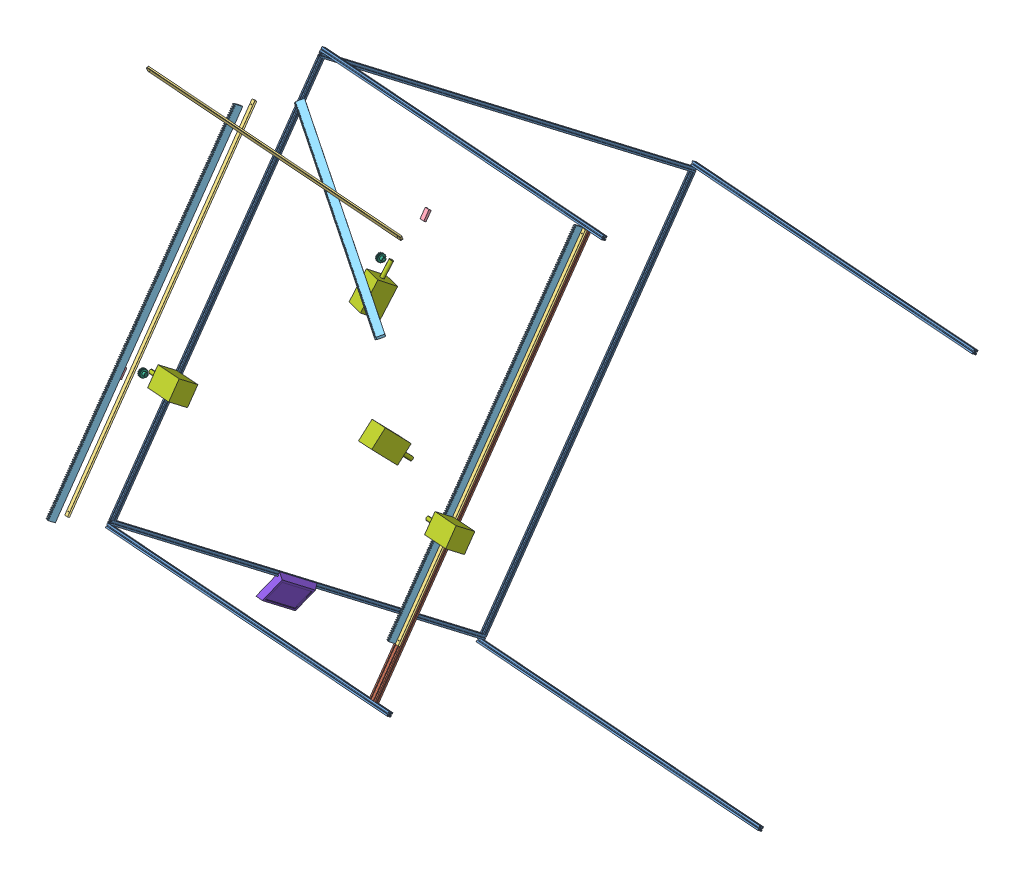
SolidWorks assembly Paketleme Kartezyen Robotu_Exoskeleton, configuration Varsayılan. Lengths in mm.
Overall size (2459.18 3444.17 3173.2).
27 component instances, 8 part files, 54 mates.
Components (placement in the parent):
- Sigma Profil-1: Sigma Profil [Varsayılan<Makinelenmiş Olarak>] at (-2463.5202 2459.5704 -5091.3721) x (0.236079 -0.555945 -0.796989) z (0.97173 0.132881 0.195148) size (20 20 2000)
- Sigma Profil-2: Sigma Profil [Varsayılan<Makinelenmiş Olarak>] at (-992.8245 2135.815 -1945.5437) x (-0.002587 -0.820529 0.571599) z (-0.97173 -0.132881 -0.195148) size (20 20 2000)
- Sigma Profil-3: Sigma Profil [Varsayılan<Makinelenmiş Olarak>] at (-2456.7194 781.4613 -3931.3276) x (0.97173 0.132881 0.195148) z (-0.236079 0.555945 0.796989) size (20 20 2000)
- Sigma Profil-4: Sigma Profil [Varsayılan<Makinelenmiş Olarak>] at (-2923.6516 3550.8201 -3491.9806) x (0.97173 0.132881 0.195148) z (0.236079 -0.555945 -0.796989) size (20 20 2000)
- Sigma Profil-5: Sigma Profil [Varsayılan<Makinelenmiş Olarak>] at (-2930.9564 3560.3424 -3513.3339) x (0.236079 -0.555945 -0.796989) z (0.97173 0.132881 0.195148) size (20 20 2000)
- Sigma Profil-6: Sigma Profil [Varsayılan<Makinelenmiş Olarak>] at (-525.3883 1035.043 -3523.5818) x (-0.002587 -0.820529 0.571599) z (-0.97173 -0.132881 -0.195148) size (20 20 2000)
- Sigma Profil-7: Sigma Profil [Varsayılan<Makinelenmiş Olarak>] at (-2453.8805 2436.2834 -5072.2726) x (0.97173 0.132881 0.195148) z (-0.002587 -0.820529 0.571599) size (20 20 2000)
- Sigma Profil-8: Sigma Profil [Varsayılan<Makinelenmiş Olarak>] at (-2921.3167 3537.0554 -3494.2345) x (0.97173 0.132881 0.195148) z (-0.002587 -0.820529 0.571599) size (20 20 2000)
- Sigma Profil_Kısa-3: Sigma Profil_Kısa [Varsayılan<Makinelenmiş Olarak>] at (-1094.4117 3803.2819 -3138.7888) x (0.97173 0.132881 0.195148) z (-0.002587 -0.820529 0.571599) size (20 20 2040)
- Sigma Profil_Kısa-4: Sigma Profil_Kısa [Varsayılan<Makinelenmiş Olarak>] at (-1113.8463 3800.6243 -3142.6918) x (0.97173 0.132881 0.195148) z (-0.002587 -0.820529 0.571599) size (20 20 2040)
- Kızak-1: Kızak [Varsayılan] at (-1108.8506 3813.072 -3124.8005) x (0.97173 0.132881 0.195148) z (-0.002587 -0.820529 0.571599) size (20 10 1800)
- Kızak Arabası-1: Kızak Arabası [Varsayılan] at (-1096.5814 2706.2184 -2355.3461) x (-0.97173 -0.132881 -0.195148) z (0.002587 0.820529 -0.571599) size (26 12 50)
- rack spur rectangular_am-1: rack spur rectangular_am [Metric - Rack-spur - rectangular 3M 20PA 12FW 40PH 1800L---SAll] at (-1118.9201 2329.4979 -2105.4525) x (0.002587 0.820529 -0.571599) z (0.97173 0.132881 0.195148) size (1800 43 12)
- Helis Dişli-1: Helis Dişli [Varsayılan] at (-1143.9191 2774.2829 -2345.3278) x (0.213667 -0.14336 -0.96633) z (0.97173 0.132881 0.195148) size (40.04 40.08 30)
- Step Motor-1: Step Motor [Varsayılan] at (-957.333 2729.3778 -2321.4707) x (-0.236079 0.555945 0.796989) z (-0.97173 -0.132881 -0.195148) size (100 100 230)
- Kızak-2: Kızak [Varsayılan] at (-2957.5628 3492.5053 -3150.1568) x (0.97173 0.132881 0.195148) z (-0.002587 -0.820529 0.571599) size (20 10 1800)
- rack spur rectangular_am-2: rack spur rectangular_am [Metric - Rack-spur - rectangular 3M 20PA 12FW 40PH 1800L---SAll] at (-2924.5679 2041.9084 -2032.0561) x (0.002587 0.820529 -0.571599) z (0.97173 0.132881 0.195148) size (1800 43 12)
- Step Motor-2: Step Motor [Varsayılan] at (-2638.6306 2513.7289 -2474.942) x (-0.236079 0.555945 0.796989) z (-0.97173 -0.132881 -0.195148) size (100 100 230)
- Helis Dişli-2: Helis Dişli [Varsayılan] at (-2903.9921 2543.6123 -2488.9151) x (0.213667 -0.14336 -0.96633) z (0.97173 0.132881 0.195148) size (40.04 40.08 30)
- Kızak Arabası-2: Kızak Arabası [Varsayılan] at (-2957.7129 2521.3875 -2419.4089) x (-0.97173 -0.132881 -0.195148) z (0.002587 0.820529 -0.571599) size (26 12 50)
- Kızak-3: Kızak [Varsayılan] at (-2931.2726 3938.6675 -2548.2487) x (-0.181367 0.949324 0.256692) z (0.97173 0.132881 0.195148) size (20 10 1800)
- rack spur rectangular_am-3: rack spur rectangular_am [Metric - Rack-spur - rectangular 3M 20PA 12FW 40PH 1800L---SAll] at (-1096.7207 3863.0566 -2021.5387) x (-0.817632 -0.068937 -0.571599) z (-0.217067 0.956451 0.195148) size (1800 43 12)
- Step Motor-3: Step Motor [Varsayılan] at (-1719.3987 3492.5616 -2446.889) x (0.944556 0.097361 0.313583) z (0.095305 0.832619 -0.545584) size (100 100 230)
- Helis Dişli-3: Helis Dişli [Varsayılan] at (-1646.4545 3696.6402 -2542.6724) x (0.213667 -0.14336 -0.96633) z (0.97173 0.132881 0.195148) size (40.04 40.08 30)
- Kızak Arabası-5: Kızak Arabası [Varsayılan] at (-1654.9521 3737.8982 -2795.7684) x (-0.97173 -0.132881 -0.195148) z (0.002587 0.820529 -0.571599) size (26 12 50)
- Step Motor-4: Step Motor [Varsayılan] at (-1973.4534 2614.7806 -2828.1373) x (0.9569 0.182078 0.22625) z (0.28821 -0.69123 -0.662673) size (100 100 230)
- HMI-3: HMI [Varsayılan] at (-2775.2957 1287.9638 -2989.7364) x (0.236079 -0.555945 -0.796989) z (0.863252 -0.25659 0.434693) size (200 150 30)
Mates (geometry in assembly coordinates):
- Çakışık2: coincident anti-aligned: plane of Sigma Profil-2 through (-2935.6693 1876.8687 -2343.5475) normal (0.002587 0.820529 -0.571599); plane of Sigma Profil-3 through (-2926.4737 1885.4791 -2331.1458) normal (-0.002587 -0.820529 0.571599)
- Çakışık3: coincident aligned: plane of Sigma Profil-2 through (-2938.6397 1877.6641 -2329.2981) normal (-0.236079 0.555945 0.796989); plane of Sigma Profil-3 through (-2928.8772 1893.3521 -2337.3496) normal (-0.236079 0.555945 0.796989)
- Çakışık4: coincident aligned: plane of Sigma Profil-2 through (-2936.2854 1870.0533 -2335.839) normal (-0.97173 -0.132881 -0.195148); plane of Sigma Profil-3 through (-2938.6009 1889.972 -2337.8721) normal (-0.97173 -0.132881 -0.195148)
- Çakışık9: coincident aligned: plane of Sigma Profil-3 through (-2938.6009 1889.972 -2337.8721) normal (-0.97173 -0.132881 -0.195148); plane of Sigma Profil-6 through (-2468.8492 769.2813 -3913.8772) normal (-0.97173 -0.132881 -0.195148)
- Çakışık10: coincident anti-aligned: plane of Sigma Profil-3 through (-2931.3324 1884.8147 -2332.1215) normal (-0.002587 -0.820529 0.571599); plane of Sigma Profil-6 through (-2469.4135 778.8765 -3917.6007) normal (0.002587 0.820529 -0.571599)
- Çakışık11: coincident aligned: plane of Sigma Profil-3 through (-2456.7194 781.4613 -3931.3276) normal (0.236079 -0.555945 -0.796989); plane of Sigma Profil-6 through (-2466.4949 761.6705 -3920.4181) normal (0.236079 -0.555945 -0.796989)
- Çakışık17: coincident anti-aligned: plane of Sigma Profil-3 through (-2931.2806 1901.2252 -2343.5535) normal (0.002587 0.820529 -0.571599); plane of Sigma Profil-7 through (-2459.0543 795.226 -3929.0737) normal (-0.002587 -0.820529 0.571599)
- Çakışık18: coincident anti-aligned: plane of Sigma Profil-3 through (-2926.422 1901.8896 -2342.5778) normal (0.002587 0.820529 -0.571599); plane of Sigma Profil-7 through (-2459.0543 795.226 -3929.0737) normal (-0.002587 -0.820529 0.571599)
- Çakışık19: coincident aligned: plane of Sigma Profil-3 through (-2938.588 1894.0747 -2340.7301) normal (-0.97173 -0.132881 -0.195148); plane of Sigma Profil-7 through (-2469.3618 795.287 -3929.0327) normal (-0.97173 -0.132881 -0.195148)
- Çakışık20: coincident aligned: plane of Sigma Profil-3 through (-2456.7194 781.4613 -3931.3276) normal (0.236079 -0.555945 -0.796989); plane of Sigma Profil-7 through (-2459.1228 789.3343 -3937.5314) normal (0.236079 -0.555945 -0.796989)
- Çakışık21: coincident anti-aligned: plane of Sigma Profil-3 through (-2931.2806 1901.2252 -2343.5535) normal (0.002587 0.820529 -0.571599); plane of Sigma Profil-8 through (-2926.4905 1895.998 -2351.0355) normal (-0.002587 -0.820529 0.571599)
- Çakışık23: coincident aligned: plane of Sigma Profil-3 through (-2938.588 1894.0747 -2340.7301) normal (-0.97173 -0.132881 -0.195148); plane of Sigma Profil-8 through (-2936.798 1896.059 -2350.9945) normal (-0.97173 -0.132881 -0.195148)
- Dik Açı3: perpendicular: plane of Sigma Profil-3 through (-2931.2806 1901.2252 -2343.5535) normal (0.002587 0.820529 -0.571599); plane of Sigma Profil-8 through (-2926.559 1890.1063 -2359.4933) normal (0.236079 -0.555945 -0.796989)
- Çakışık26: coincident aligned: plane of Sigma Profil-3 through (-2928.8772 1893.3521 -2337.3496) normal (-0.236079 0.555945 0.796989); plane of Sigma Profil-8 through (-2926.422 1901.8896 -2342.5778) normal (-0.236079 0.555945 0.796989)
- Paralel9: parallel aligned: plane of Sigma Profil-4 through (-2453.8973 2446.8023 -5092.1624) normal (0.002587 0.820529 -0.571599); plane of Sigma Profil-8 through (-2921.3167 3537.0554 -3494.2345) normal (0.002587 0.820529 -0.571599)
- Paralel10: parallel aligned: plane of Sigma Profil-4 through (-2461.2047 2439.6517 -5089.339) normal (-0.97173 -0.132881 -0.195148); plane of Sigma Profil-8 through (-2935.6176 1893.2793 -2354.9795) normal (-0.97173 -0.132881 -0.195148)
- Çakışık36: coincident aligned: plane of Sigma Profil-4 through (-2923.6516 3550.8201 -3491.9806) normal (-0.236079 0.555945 0.796989); plane of Sigma Profil-8 through (-2931.2806 1901.2252 -2343.5535) normal (-0.236079 0.555945 0.796989)
- Çakışık38: coincident anti-aligned: plane of Sigma Profil-4 through (-2453.949 2430.3917 -5080.7304) normal (-0.002587 -0.820529 0.571599); plane of Sigma Profil-7 through (-2453.8805 2436.2834 -5072.2726) normal (0.002587 0.820529 -0.571599)
- Çakışık39: coincident aligned: plane of Sigma Profil-4 through (-2461.2176 2435.5491 -5086.481) normal (-0.97173 -0.132881 -0.195148); plane of Sigma Profil-7 through (-2469.3618 795.287 -3929.0327) normal (-0.97173 -0.132881 -0.195148)
- Çakışık40: coincident aligned: plane of Sigma Profil-4 through (-2923.6516 3550.8201 -3491.9806) normal (-0.236079 0.555945 0.796989); plane of Sigma Profil-5 through (-989.8498 3833.7149 -3116.4977) normal (-0.236079 0.555945 0.796989)
- Çakışık41: coincident anti-aligned: plane of Sigma Profil-4 through (-2453.8973 2446.8023 -5092.1624) normal (0.002587 0.820529 -0.571599); plane of Sigma Profil-5 through (-988.1116 3819.2887 -3115.3301) normal (-0.002587 -0.820529 0.571599)
- Çakışık42: coincident aligned: plane of Sigma Profil-4 through (-2461.2047 2439.6517 -5089.339) normal (-0.97173 -0.132881 -0.195148); plane of Sigma Profil-5 through (-2930.9564 3560.3424 -3513.3339) normal (-0.97173 -0.132881 -0.195148)
- Paralel14: parallel anti-aligned: plane of Sigma Profil-1 through (-522.4266 2728.8403 -4691.6779) normal (-0.236079 0.555945 0.796989); plane of Sigma Profil-4 through (-2451.4938 2438.9292 -5085.9585) normal (0.236079 -0.555945 -0.796989)
- Dik Açı7: perpendicular: plane of Sigma Profil-1 through (-2463.5202 2459.5704 -5091.3721) normal (-0.97173 -0.132881 -0.195148); plane of Sigma Profil-4 through (-2453.8973 2446.8023 -5092.1624) normal (0.002587 0.820529 -0.571599)
- Çakışık47: coincident aligned: plane of Sigma Profil-1 through (-2463.5202 2459.5704 -5091.3721) normal (-0.97173 -0.132881 -0.195148); plane of Sigma Profil-4 through (-2461.2047 2439.6517 -5089.339) normal (-0.97173 -0.132881 -0.195148)
- Paralel12: parallel aligned: plane of Sigma Profil-1 through (-517.705 2717.7213 -4707.6176) normal (0.236079 -0.555945 -0.796989); plane of Sigma Profil-7 through (-2459.1228 789.3343 -3937.5314) normal (0.236079 -0.555945 -0.796989)
- Çakışık49: coincident anti-aligned: plane of Sigma Profil-1 through (-520.6754 2718.5167 -4693.3683) normal (-0.002587 -0.820529 0.571599); plane of Sigma Profil-4 through (-2453.8973 2446.8023 -5092.1624) normal (0.002587 0.820529 -0.571599)
- Çakışık68: coincident aligned: plane of Sigma Profil-1 through (-517.705 2717.7213 -4707.6176) normal (0.236079 -0.555945 -0.796989); plane of Sigma Profil-7 through (-2459.1228 789.3343 -3937.5314) normal (0.236079 -0.555945 -0.796989)
- Çakışık75: coincident anti-aligned: plane of Sigma Profil-5 through (-988.1116 3819.2887 -3115.3301) normal (-0.002587 -0.820529 0.571599); plane of Sigma Profil_Kısa-3 through (-1094.4117 3803.2819 -3138.7888) normal (0.002587 0.820529 -0.571599)
- Uzaklık3: distance = 100 mm aligned: plane of Sigma Profil-5 through (-987.4955 3826.1041 -3123.0386) normal (0.97173 0.132881 0.195148); plane of Sigma Profil_Kısa-3 through (-1090.5619 2132.1221 -1968.7819) normal (0.97173 0.132881 0.195148)
- Çakışık77: coincident aligned: plane of Sigma Profil-5 through (-989.8628 3829.6122 -3113.6397) normal (-0.236079 0.555945 0.796989); plane of Sigma Profil_Kısa-3 through (-1104.4791 2134.6306 -1965.2439) normal (-0.236079 0.555945 0.796989)
- Çakışık78: coincident aligned: plane of Sigma Profil-5 through (-989.8628 3829.6122 -3113.6397) normal (-0.236079 0.555945 0.796989); plane of Sigma Profil_Kısa-4 through (-1119.0551 2132.6374 -1968.1711) normal (-0.236079 0.555945 0.796989)
- Çakışık80: coincident anti-aligned: plane of Sigma Profil-5 through (-988.1116 3819.2887 -3115.3301) normal (-0.002587 -0.820529 0.571599); plane of Sigma Profil_Kısa-4 through (-1113.8463 3800.6243 -3142.6918) normal (0.002587 0.820529 -0.571599)
- Çakışık81: coincident anti-aligned: plane of Sigma Profil_Kısa-3 through (-1109.9965 2129.4644 -1972.6849) normal (-0.97173 -0.132881 -0.195148); plane of Sigma Profil_Kısa-4 through (-1109.9965 2129.4644 -1972.6849) normal (0.97173 0.132881 0.195148)
- Paralel21: parallel aligned: plane of Sigma Profil_Kısa-3 through (-1099.6205 2135.295 -1964.2681) normal (-0.236079 0.555945 0.796989); plane of Kızak-1 through (-1113.507 2336.1204 -2095.9215) normal (-0.236079 0.555945 0.796989)
- Paralel22: parallel aligned: plane of Sigma Profil-5 through (-989.8628 3829.6122 -3113.6397) normal (-0.236079 0.555945 0.796989); plane of Kızak-1 through (-1113.507 2336.1204 -2095.9215) normal (-0.236079 0.555945 0.796989)
- Çakışık86: coincident anti-aligned: plane of Sigma Profil_Kısa-3 through (-1099.6205 2135.295 -1964.2681) normal (-0.236079 0.555945 0.796989); plane of Kızak-1 through (-1091.7116 2333.2185 -2099.9884) normal (0.236079 -0.555945 -0.796989)
- Çakışık87: coincident anti-aligned: plane of Sigma Profil-5 through (-988.1116 3819.2887 -3115.3301) normal (-0.002587 -0.820529 0.571599); plane of Kızak-1 through (-1108.8506 3813.072 -3124.8005) normal (0.002587 0.820529 -0.571599)
- Çakışık89: coincident aligned: line of Sigma Profil_Kısa-3 through (-1092.3325 2136.2916 -1962.8045) axis (0.002587 0.820529 -0.571599); line of Kızak-1 through (-1091.7116 2333.2185 -2099.9884) axis (0.002587 0.820529 -0.571599)
- Paralel23: parallel aligned: plane of Kızak-1 through (-1113.507 2336.1204 -2095.9215) normal (-0.236079 0.555945 0.796989); plane of Kızak Arabası-1 through (-1115.5957 2748.7446 -2381.8598) normal (-0.236079 0.555945 0.796989)
- Çakışık93: coincident anti-aligned: plane of Kızak-1 through (-1097.7507 2335.3339 -2096.9792) normal (0.520184 0.487074 0.701547); plane of Kızak Arabası-1 through (-1096.452 2747.2449 -2383.926) normal (-0.520184 -0.487074 -0.701547)
- Çakışık94: coincident anti-aligned: plane of Kızak-1 through (-1113.507 2336.1204 -2095.9215) normal (-0.236079 0.555945 0.796989); plane of Kızak Arabası-1 through (-1092.7738 2750.689 -2378.9653) normal (0.236079 -0.555945 -0.796989)
- Paralel25: parallel aligned: line of Kızak-1 through (-1094.0724 2338.778 -2092.0185) axis (0.002587 0.820529 -0.571599); line of rack spur rectangular_am-1 through (-1118.9201 2329.4979 -2105.4525) axis (0.002587 0.820529 -0.571599)
- Çakışık103: coincident anti-aligned: plane of Sigma Profil_Kısa-4 through (-1123.9137 2131.973 -1969.1468) normal (-0.236079 0.555945 0.796989); plane of rack spur rectangular_am-1 through (-1130.5808 2327.9033 -2107.7943) normal (0.236079 -0.555945 -0.796989)
- Çakışık104: coincident aligned: line of Sigma Profil_Kısa-4 through (-1131.2017 2130.9764 -1970.6104) axis (0.002587 0.820529 -0.571599); line of rack spur rectangular_am-1 through (-1130.5808 2327.9033 -2107.7943) axis (0.002587 0.820529 -0.571599)
- Çakışık105: coincident anti-aligned: line of Sigma Profil-5 through (-989.8822 3823.4583 -3109.3527) axis (-0.97173 -0.132881 -0.195148); line of rack spur rectangular_am-1 through (-1125.9244 3804.855 -3136.6734) axis (0.97173 0.132881 0.195148)
- Eş Merkezli2: concentric aligned: cylinder of Helis Dişli-1 through (-1153.6364 2772.9541 -2347.2793) axis (0.97173 0.132881 0.195148) radius 5; cylinder of Step Motor-1 through (-1192.5056 2767.6389 -2355.0852) axis (0.97173 0.132881 0.195148) radius 10
- Uzaklık10: distance = 50 mm aligned: plane of Helis Dişli-1 through (-1143.9191 2774.2829 -2345.3278) normal (-0.97173 -0.132881 -0.195148); plane of Step Motor-1 through (-1192.5056 2767.6389 -2355.0852) normal (-0.97173 -0.132881 -0.195148)
- Paralel26: parallel aligned: plane of rack spur rectangular_am-1 through (-1140.7322 2351.809 -2073.5238) normal (-0.97173 -0.132881 -0.195148); plane of Step Motor-1 through (-1103.0926 2709.4456 -2350.7429) normal (-0.97173 -0.132881 -0.195148)
- Çakışık107: coincident anti-aligned: plane of Kızak Arabası-1 through (-1115.5957 2748.7446 -2381.8598) normal (-0.236079 0.555945 0.796989); plane of Step Motor-1 through (-1103.0926 2709.4456 -2350.7429) normal (0.236079 -0.555945 -0.796989)
- Uzaklık11: distance = 30 mm aligned: plane of Step Motor-1 through (-1103.0926 2709.4456 -2350.7429) normal (-0.97173 -0.132881 -0.195148); plane of rack spur rectangular_am-1 through (-1140.7322 2351.809 -2073.5238) normal (-0.97173 -0.132881 -0.195148)
- Çakışık109: coincident aligned: line of Kızak Arabası-1 through (-1115.7251 2707.7182 -2353.2798) axis (0.97173 0.132881 0.195148); line of Step Motor-1 through (-1103.0926 2709.4456 -2350.7429) axis (0.97173 0.132881 0.195148)
- Paralel27: parallel aligned: line of Sigma Profil-5 through (-986.9312 3816.509 -3119.3151) axis (-0.97173 -0.132881 -0.195148); line of Kızak-3 through (-1185.7851 4196.8395 -2191.849) axis (-0.97173 -0.132881 -0.195148)
- Çakışık114: coincident anti-aligned: line of Sigma Profil-3 through (-2919.134 1902.8862 -2341.1141) axis (0.236079 -0.555945 -0.796989); line of HMI-3 through (-2661.1552 1295.3683 -3212.036) axis (-0.236079 0.555945 0.796989)
